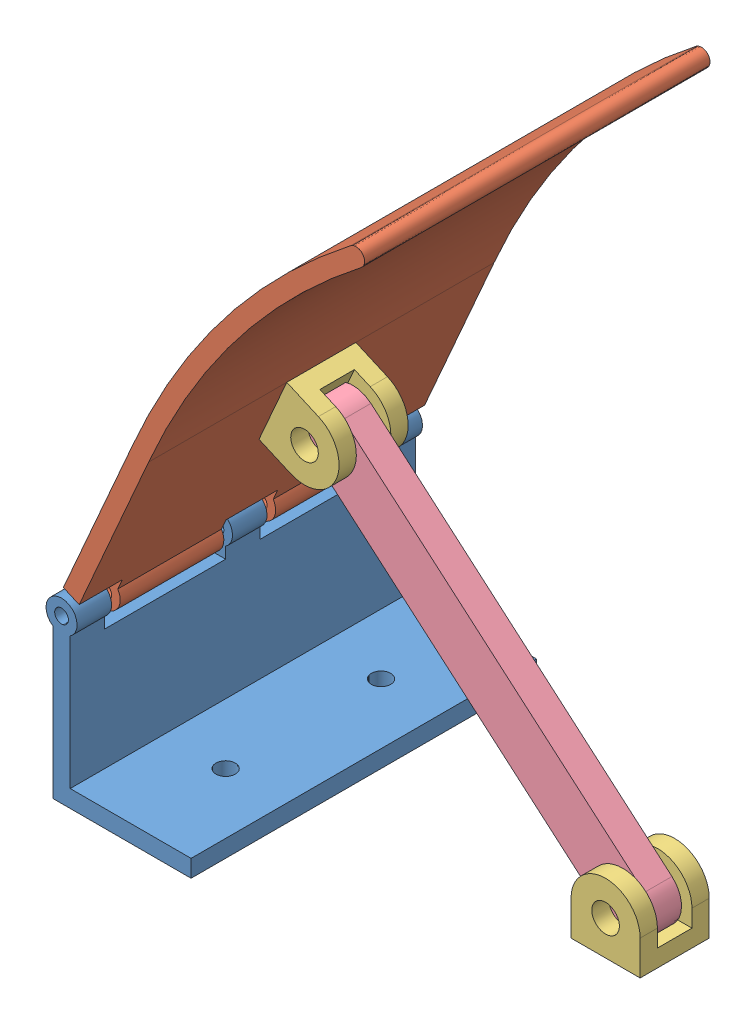
SolidWorks assembly Assembly_front, configuration Default. Lengths in mm.
Overall size (134.71 195.05 100).
5 component instances, 4 part files, 12 mates.
Components (placement in the parent):
- Front_mount-1: Front_mount [Default] at (12.7713 30.8711 76.6768) size (42 51.5 100)
- Front-1: Front [Default] at (15.7957 85.2857 76.6768) x (0.915668 -0.401935 0) z (0 0 1) size (31.7 162.81 100)
- Bar_mount-1: Bar_mount [Default] at (32.4365 110.7562 86.6768) x (0 0 -1) z (0.915668 -0.401935 0) size (20 20 20)
- Bar_mount-2: Bar_mount [Default] at (142.7713 30.8711 86.6768) x (0 0 -1) z (0 1 0) size (20 20 20)
- Bar-1: Bar [Default] at (127.5524 34.8079 76.6768) x (0.652368 0.757902 0) z (0 0 1) size (16 131 8)
Mates (geometry in assembly coordinates):
- Concentric1: concentric: cylinder of Front_mount-1 through (15.2713 77.8711 116.6768) axis (0 0 1) radius 2; cylinder of Front-1 through (15.2713 77.8711 84.1768) axis (0 0 1) radius 2
- Distance1: distance = 2.5 mm: plane of Front-1 through (15.7957 85.2857 114.1768) normal (0 0 1); plane of Front_mount-1 through (15.2713 77.8711 116.6768) normal (0 0 -1)
- Coincident3: coincident: plane of Front-1 through (20.374 83.276 126.6768) normal (0.915668 -0.401935 0); plane of Bar_mount-1 through (32.4365 110.7562 86.6768) normal (-0.915668 0.401935 0)
- Coincident4: coincident: line of Front-1 through (40.4753 129.0695 126.6768) axis (0 0 -1); line of Bar_mount-1 through (40.4753 129.0695 66.6768) axis (0 0 1)
- Coincident7: coincident: moEndPointRef_w of Front-1; moEndPointRef_w of Bar_mount-1
- Coincident8: coincident: plane of Front_mount-1 through (12.7713 30.8711 126.6768) normal (0 -1 0); plane of Bar_mount-2 through (142.7713 30.8711 130.3135) normal (0 -1 0)
- Parallel2: parallel: line of Front_mount-1 through (52.7713 30.8711 126.6768) axis (0 0 -1); line of Bar_mount-2 through (122.7713 30.8711 110.3135) axis (0 0 1)
- Distance2: distance = 70 mm: line of Front_mount-1 through (52.7713 30.8711 126.6768) axis (0 0 -1); line of Bar_mount-2 through (122.7713 30.8711 66.6768) axis (0 0 1)
- Concentric2: concentric: cylinder of Bar_mount-1 through (45.6126 115.8935 86.6768) axis (0 0 -1) radius 4; cylinder of Bar-1 through (45.6126 115.8935 72.6768) axis (0 0 1) radius 4
- Concentric3: concentric: cylinder of Bar_mount-2 through (132.7713 40.8711 130.3135) axis (0 0 -1) radius 4; cylinder of Bar-1 through (132.7713 40.8711 72.6768) axis (0 0 1) radius 4
- Distance3: distance = 1 mm: plane of Bar_mount-1 through (41.5932 106.7368 81.6768) normal (0 0 -1); plane of Bar-1 through (132.7713 40.8711 80.6768) normal (0 0 1)
- Distance4: distance = 1 mm: plane of Bar_mount-2 through (142.7713 40.8711 81.6768) normal (0 0 -1); plane of Bar-1 through (132.7713 40.8711 80.6768) normal (0 0 1)
